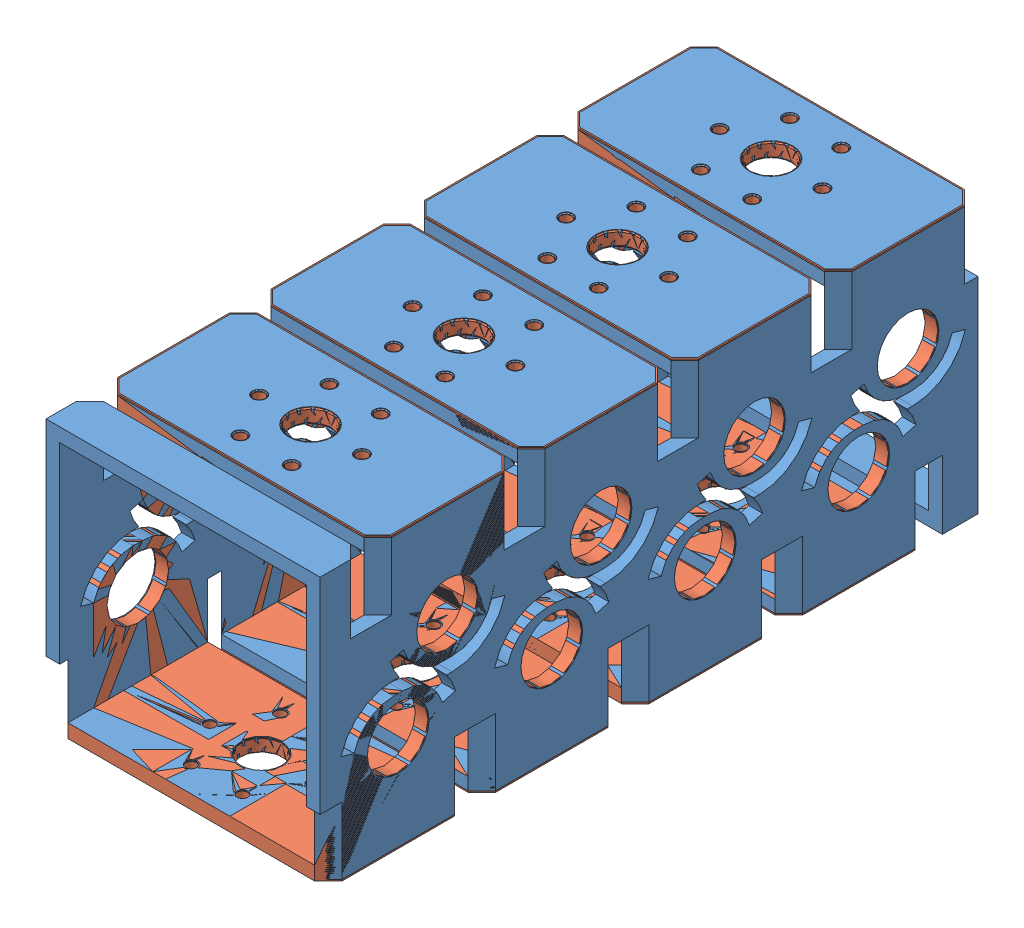
SolidWorks assembly BB_Swerve_Saddle_Assem, configuration Default. Lengths in mm.
Overall size (127 127 304.8).
9 component instances, 2 part files, 27 mates.
Components (placement in the parent):
- BB_Swerve_Saddle_Stock-1: BB_Swerve_Saddle_Stock [Default] at origin size (127 127 304.8)
- BB_Swerve_Saddle-1: BB_Swerve_Saddle [Default] at (63.5 120.65 32.385) size (127 62.23 64.77)
- BB_Swerve_Saddle-2: BB_Swerve_Saddle [Default] at (63.5 6.35 55.245) x (-1 0 0) z (0 0 1) size (127 62.23 64.77)
- BB_Swerve_Saddle-3: BB_Swerve_Saddle [Default] at (63.5 120.65 103.505) size (127 62.23 64.77)
- BB_Swerve_Saddle-4: BB_Swerve_Saddle [Default] at (63.5 120.65 174.625) size (127 62.23 64.77)
- BB_Swerve_Saddle-5: BB_Swerve_Saddle [Default] at (63.5 120.65 245.745) size (127 62.23 64.77)
- BB_Swerve_Saddle-6: BB_Swerve_Saddle [Default] at (63.5 6.35 126.365) x (-1 0 0) z (0 0 1) size (127 62.23 64.77)
- BB_Swerve_Saddle-7: BB_Swerve_Saddle [Default] at (63.5 6.35 197.485) x (-1 0 0) z (0 0 1) size (127 62.23 64.77)
- BB_Swerve_Saddle-8: BB_Swerve_Saddle [Default] at (63.5 6.35 268.605) x (-1 0 0) z (0 0 1) size (127 62.23 64.77)
Mates (geometry in assembly coordinates):
- Coincident1: coincident aligned: plane of BB_Swerve_Saddle_Stock-1 through (0 127 304.8) normal (0 1 0); plane of BB_Swerve_Saddle-1 through (63.5 127 32.385) normal (0 1 0)
- Coincident2: coincident aligned: plane of BB_Swerve_Saddle_Stock-1 through (0 0 0) normal (0 0 -1); plane of BB_Swerve_Saddle-1 through (120.65 120.65 0) normal (0 0 -1)
- Coincident3: coincident aligned: plane of BB_Swerve_Saddle_Stock-1 through (0 0 304.8) normal (-1 0 0); plane of BB_Swerve_Saddle-1 through (0 120.65 32.385) normal (-1 0 0)
- Coincident4: coincident aligned: plane of BB_Swerve_Saddle_Stock-1 through (0 0 304.8) normal (0 -1 0); plane of BB_Swerve_Saddle-2 through (63.5 0 55.245) normal (0 -1 0)
- Coincident6: coincident aligned: plane of BB_Swerve_Saddle_Stock-1 through (0 0 304.8) normal (-1 0 0); plane of BB_Swerve_Saddle-2 through (0 6.35 55.245) normal (-1 0 0)
- Coincident7: coincident aligned: plane of BB_Swerve_Saddle_Stock-1 through (0 127 304.8) normal (0 1 0); plane of BB_Swerve_Saddle-3 through (63.5 127 103.505) normal (0 1 0)
- Coincident8: coincident aligned: plane of BB_Swerve_Saddle_Stock-1 through (0 0 304.8) normal (-1 0 0); plane of BB_Swerve_Saddle-3 through (0 120.65 103.505) normal (-1 0 0)
- Parallel1: parallel aligned: plane of BB_Swerve_Saddle-1 through (120.65 120.65 0) normal (0 0 -1); plane of BB_Swerve_Saddle-3 through (120.65 120.65 71.12) normal (0 0 -1)
- Coincident9: coincident aligned: plane of BB_Swerve_Saddle_Stock-1 through (0 127 304.8) normal (0 1 0); plane of BB_Swerve_Saddle-4 through (63.5 127 174.625) normal (0 1 0)
- Coincident10: coincident aligned: plane of BB_Swerve_Saddle_Stock-1 through (0 0 304.8) normal (-1 0 0); plane of BB_Swerve_Saddle-4 through (0 120.65 174.625) normal (-1 0 0)
- Parallel2: parallel aligned: line of BB_Swerve_Saddle-1 through (114.3 120.65 127) axis (0 -1 0); line of BB_Swerve_Saddle-4 through (120.65 127 142.24) axis (-1 0 0)
- Coincident11: coincident aligned: plane of BB_Swerve_Saddle_Stock-1 through (0 127 304.8) normal (0 1 0); plane of BB_Swerve_Saddle-5 through (63.5 127 245.745) normal (0 1 0)
- Coincident12: coincident aligned: plane of BB_Swerve_Saddle_Stock-1 through (0 0 304.8) normal (-1 0 0); plane of BB_Swerve_Saddle-5 through (0 120.65 245.745) normal (-1 0 0)
- Parallel3: parallel aligned: line of BB_Swerve_Saddle-1 through (114.3 120.65 127) axis (0 -1 0); line of BB_Swerve_Saddle-5 through (120.65 127 213.36) axis (-1 0 0)
- Distance3: distance = 6.35 mm: line of BB_Swerve_Saddle-5 through (120.65 127 213.36) axis (-1 0 0); line of BB_Swerve_Saddle-4 through (6.35 127 207.01) axis (1 0 0)
- Coincident14: coincident aligned: plane of BB_Swerve_Saddle_Stock-1 through (0 0 304.8) normal (0 -1 0); plane of BB_Swerve_Saddle-6 through (63.5 0 126.365) normal (0 -1 0)
- Coincident15: coincident aligned: plane of BB_Swerve_Saddle_Stock-1 through (127 0 304.8) normal (1 0 0); plane of BB_Swerve_Saddle-6 through (127 6.35 126.365) normal (1 0 0)
- Coincident17: coincident aligned: plane of BB_Swerve_Saddle_Stock-1 through (0 0 304.8) normal (0 -1 0); plane of BB_Swerve_Saddle-7 through (63.5 0 197.485) normal (0 -1 0)
- Coincident18: coincident aligned: plane of BB_Swerve_Saddle_Stock-1 through (127 0 304.8) normal (1 0 0); plane of BB_Swerve_Saddle-7 through (127 6.35 197.485) normal (1 0 0)
- Coincident20: coincident aligned: plane of BB_Swerve_Saddle_Stock-1 through (0 0 304.8) normal (0 -1 0); plane of BB_Swerve_Saddle-8 through (63.5 0 268.605) normal (0 -1 0)
- Coincident21: coincident aligned: plane of BB_Swerve_Saddle_Stock-1 through (127 0 304.8) normal (1 0 0); plane of BB_Swerve_Saddle-8 through (127 6.35 268.605) normal (1 0 0)
- Distance4: distance = 6.35 mm: plane of BB_Swerve_Saddle-4 through (120.65 120.65 142.24) normal (0 0 -1); line of BB_Swerve_Saddle-3 through (6.35 120.65 135.89) axis (1 0 0)
- Distance5: distance = 6.35 mm: plane of BB_Swerve_Saddle-6 through (6.35 6.35 93.98) normal (0 0 -1); line of BB_Swerve_Saddle-2 through (120.65 0 87.63) axis (-1 0 0)
- Distance6: distance = 6.35 mm: plane of BB_Swerve_Saddle-7 through (6.35 6.35 165.1) normal (0 0 -1); line of BB_Swerve_Saddle-6 through (120.65 0 158.75) axis (-1 0 0)
- Distance7: distance = 6.35 mm: plane of BB_Swerve_Saddle-8 through (6.35 6.35 236.22) normal (0 0 -1); line of BB_Swerve_Saddle-7 through (120.65 0 229.87) axis (-1 0 0)
- Distance8: distance = 6.35 mm anti-aligned: plane of BB_Swerve_Saddle-1 through (6.35 120.65 64.77) normal (0 0 1); plane of BB_Swerve_Saddle-3 through (120.65 120.65 71.12) normal (0 0 -1)
- Distance9: distance = 22.86 mm: line of BB_Swerve_Saddle_Stock-1 through (127 0 0) axis (0 1 0); line of BB_Swerve_Saddle-2 through (6.35 0 22.86) axis (1 0 0)
